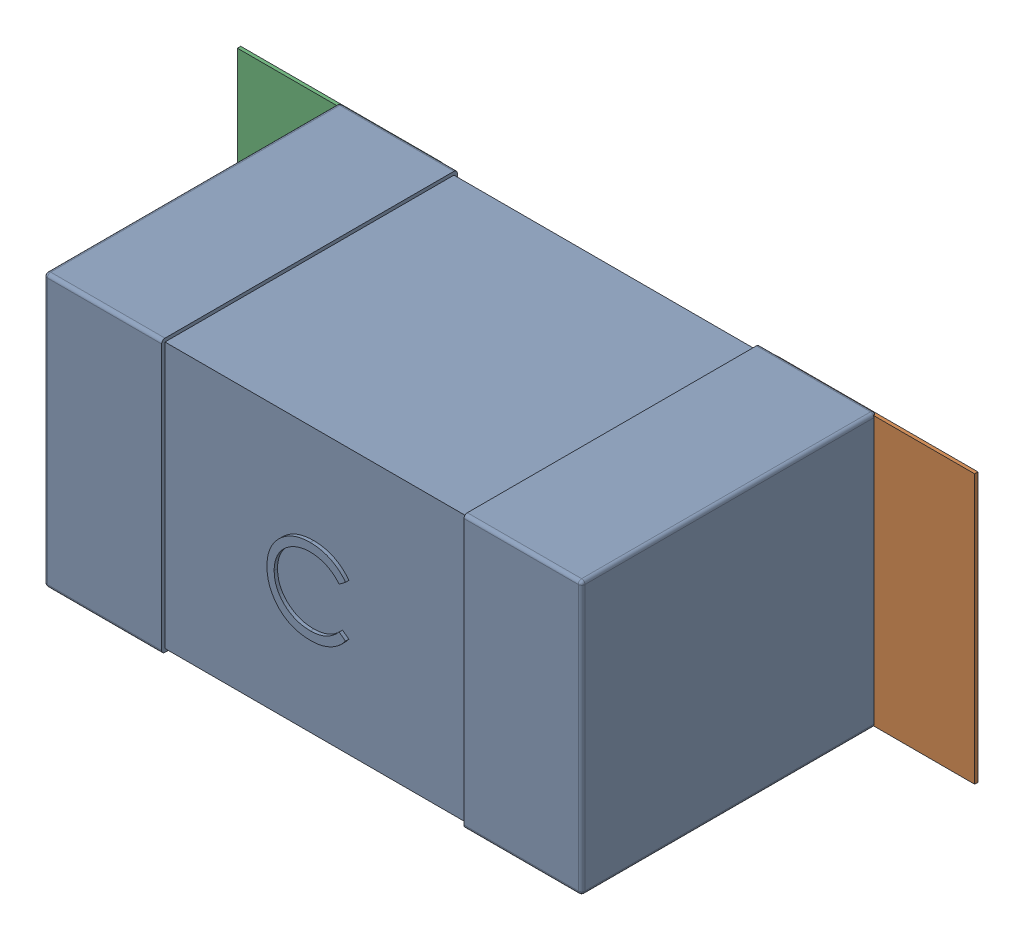
SolidWorks assembly C37, configuration Défaut. Lengths in mm.
Overall size (2.19 0.81 0.88).
5 component instances, 2 part files, 0 mates.
Components (placement in the parent):
- 0603_C-1: 0603_C [Défaut] at (8.9379 -11.6907 0) x (1 0 0) z (0 0 1) size (1.6 0.81 0.88)
- 6634915696-1: 6634915696 [Défaut] at (10.1879 -11.6907 0) size (0.6 0.8 0.01)
  - Extruded_497-1: Extruded_497 [Défaut] at origin size (0.6 0.8 0.01)
- 6634915696-2: 6634915696 [Défaut] at (8.593 -11.6907 0) size (0.6 0.8 0.01)
  - Extruded_497-1: Extruded_497 [Défaut] at origin size (0.6 0.8 0.01)
